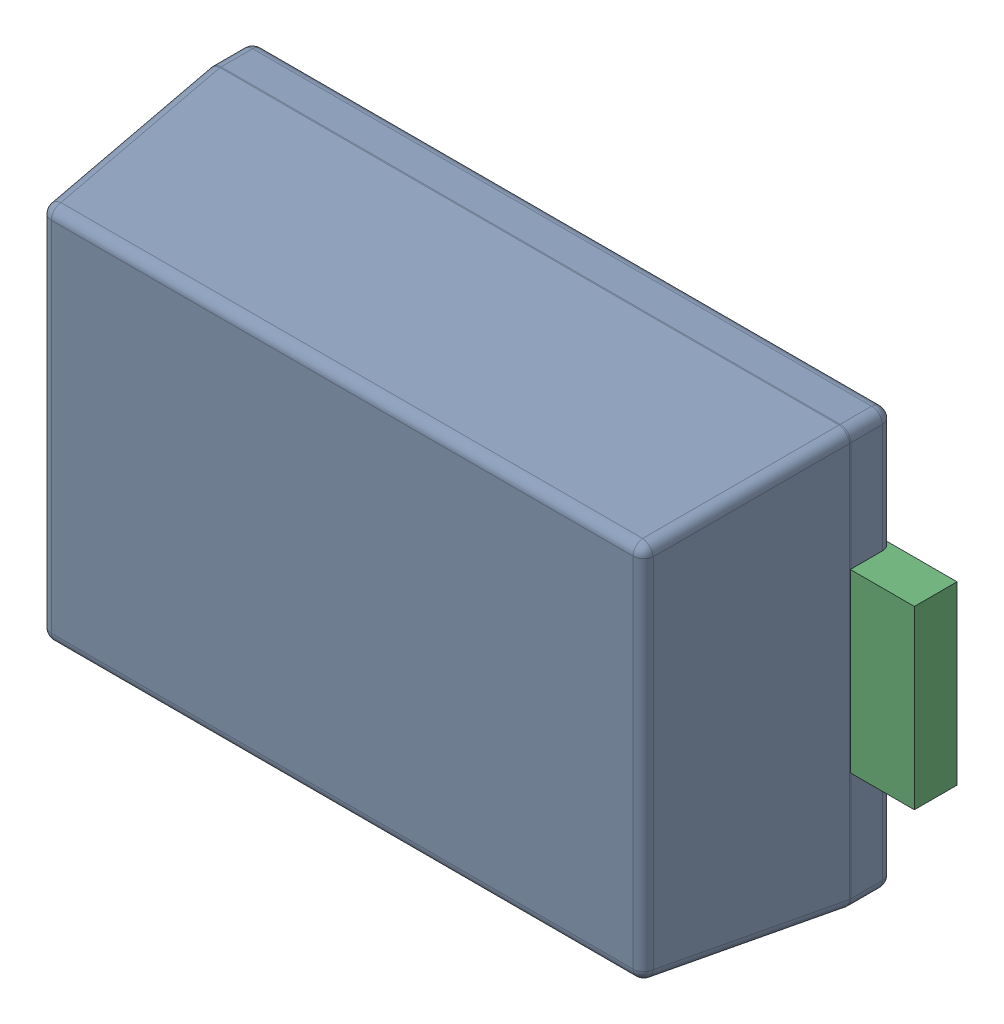
SolidWorks assembly D4, configuration Default. Lengths in mm.
Overall size (3.6 1.96 1.08).
5 component instances, 2 part files, 0 mates.
Components (placement in the parent):
- 809534704-1: 809534704 [Default] at (117.5503 75.311 0) x (1 0 0) z (0 0 1) size (3.6 1.96 1.08)
  - Body_3-1: Body_3 [Default] at (-1.5 -0.975 0) size (3.01 1.96 1.08)
    - Open_CASCADE_STEP_translator_6.8_1.1.1_2-1: Open_CASCADE_STEP_translator_6.8_1.1.1_2 [Default] at origin size (3.01 1.96 1.08)
  - lead_2-1: lead_2 [Default] at (-1.8 -0.4125 0) size (0.68 0.82 0.2)
  - lead_2-2: lead_2 [Default] at (1.8 0.4125 0) x (-1 0 0) z (0 0 1) size (0.68 0.82 0.2)
